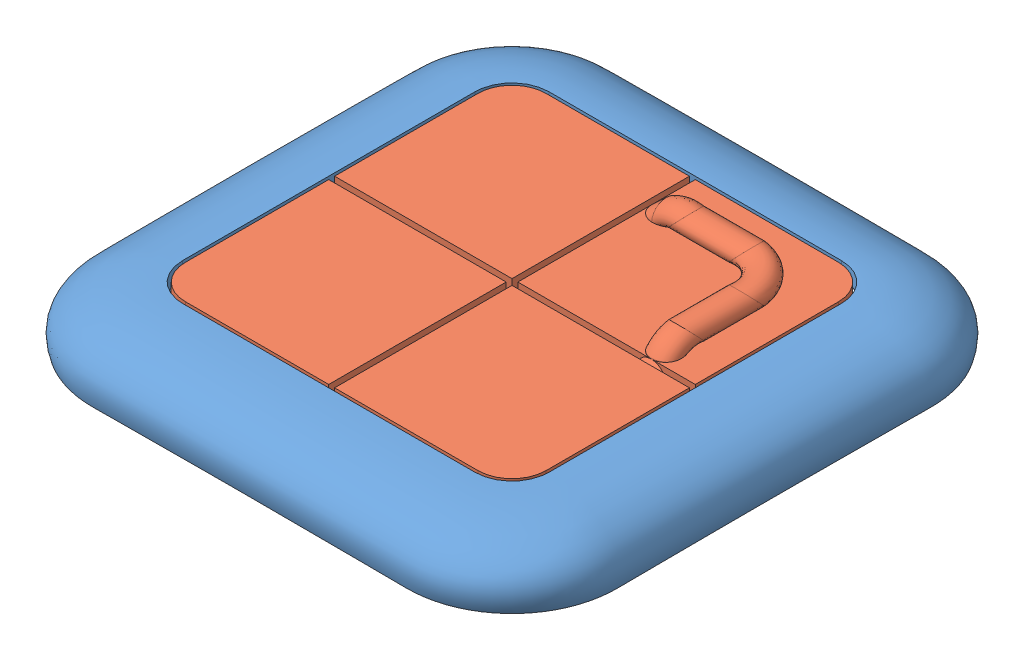
SolidWorks assembly Remote Assembly, configuration Default. Lengths in mm.
Overall size (47.49 9.02 47.49).
4 component instances, 4 part files, 4 mates.
Components (placement in the parent):
- Remote Top-1: Remote Top [Default] at (4.1672 24.4268 39.9733) size (47.49 7.42 47.49)
- Remote Bottom-1: Remote Bottom [Default] at (4.1672 24.4268 39.9733) size (47.49 15.9 47.49) (hidden)
- PCB-3: PCB [Default] at (-14.2196 31.6968 58.3883) x (0 0 -1) z (0 -1 0) size (36.83 36.86 1.03) (hidden)
- Remote Buttons-1: Remote Buttons [Default] at (4.1672 35.8568 39.9733) size (37.5 6.36 31.24)
Mates (geometry in assembly coordinates):
- Coincident1: coordinate: point of Remote Top-1; point of Remote Bottom-1
- Coincident13: coincident: line of Remote Bottom-1 through (4.1672 24.4268 39.9733) axis (0 1 0); point of PCB-3
- Coincident14: coincident: line of Remote Bottom-1 through (4.1672 24.4268 39.9733) axis (0 1 0); point of PCB-3
- Coincident17: coincident: point of Remote Top-1; point of Remote Buttons-1
